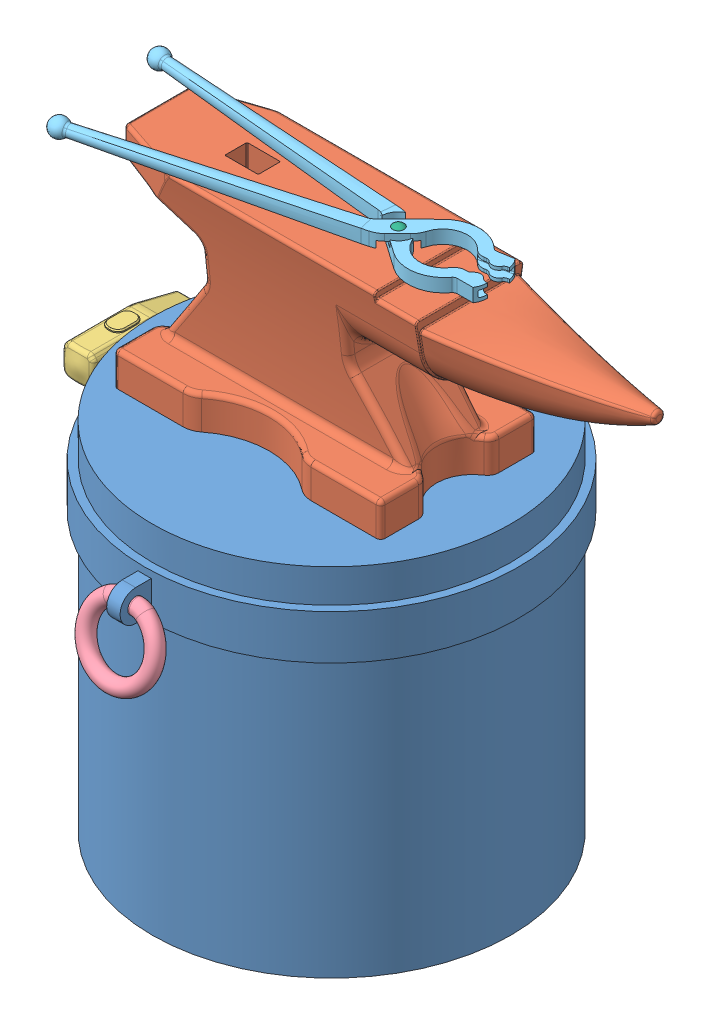
SolidWorks assembly Сборка1, configuration По умолчанию. Lengths in mm.
Overall size (2519.05 2545.47 1870.89).
7 component instances, 6 part files, 11 mates.
Components (placement in the parent):
- Дет0-1: Дет0 [По умолчанию] at (696.6225 706.2106 707.0995) size (1880 1630.94 1820)
- Дет1-1: Дет1 [По умолчанию] at (675.67 2306.2106 715.6378) size (2250 850 700)
- Дет2-1: Дет2 [По умолчанию] at (-243.3775 2146.2106 707.0995) x (0 1 0) z (-1 0 0) size (900 515.77 140.28)
- Дет3-1: Дет3 [По умолчанию] at (696.6225 2056.2106 1617.0995) x (1 0 0) z (0 0.268213 0.96336) size (370 360 70)
- Дет4-1: Дет4 [По умолчанию] at (1012.0301 3196.2106 722.3721) size (1678.58 80 330.31)
- Дет5-1: Дет5 [По умолчанию] at (1012.0301 3196.2106 722.3721) size (50 80 50)
- Дет4-2: Дет4 [По умолчанию] at (1012.0301 3196.2106 722.3721) x (0.98633 0 -0.16478) z (-0.16478 0 -0.98633) size (1678.58 80 330.31)
Mates (geometry in assembly coordinates):
- Совпадение2: coincident anti-aligned: plane of Дет0-1 through (-238.3775 2076.2106 772.0995) normal (0 0 -1); plane of Дет2-1 through (-288.3775 2090.3527 772.0995) normal (0 0 1)
- Совпадение3: coincident anti-aligned: plane of Дет0-1 through (-198.3775 2076.2106 732.0995) normal (-1 0 0); plane of Дет2-1 through (-198.3775 2146.2106 707.0995) normal (1 0 0)
- Совпадение4: coincident anti-aligned: plane of Дет0-1 through (696.6225 2076.2106 707.0995) normal (0 1 0); plane of Дет2-1 through (-313.3775 2076.2106 625.5653) normal (0 -1 0)
- Совпадение5: coincident anti-aligned: plane of Дет0-1 through (666.6225 2056.2106 1617.0995) normal (-1 0 0); plane of Дет3-1 through (666.6225 2056.2106 1617.0995) normal (1 0 0)
- Концентричный1: concentric aligned: cylinder of Дет0-1 through (726.6225 2056.2106 1617.0995) axis (-1 0 0) radius 30; cylinder of Дет3-1 through (646.366 2056.2106 1617.0995) axis (-1 0 0) radius 30
- Совпадение6: coincident anti-aligned: plane of Дет0-1 through (696.6225 2306.2106 707.0995) normal (0 1 0); plane of Дет1-1 through (95.67 2306.2106 385.6378) normal (0 -1 0)
- Совпадение7: coincident anti-aligned: plane of Дет4-1 through (1199.1316 3166.2106 703.4891) normal (0 -1 0); plane of Дет5-1 through (1027.0301 3166.2106 722.3721) normal (0 1 0)
- Концентричный2: concentric anti-aligned: cylinder of Дет4-1 through (1012.0301 3226.2106 722.3721) axis (0 -1 0) radius 15; cylinder of Дет5-1 through (1012.0301 3275.8827 722.3721) axis (0 1 0) radius 15
- Совпадение8: coincident anti-aligned: plane of Дет4-1 through (1012.0301 3196.2106 722.3721) normal (0 1 0); plane of Дет4-2 through (1012.0301 3196.2106 722.3721) normal (0 -1 0)
- Концентричный3: concentric aligned: cylinder of Дет5-1 through (1012.0301 3275.8827 722.3721) axis (0 1 0) radius 15; cylinder of Дет4-2 through (1012.0301 3166.2106 722.3721) axis (0 1 0) radius 15
- Касательность1: tangent anti-aligned: plane of Дет1-1 through (-74.33 3156.2106 965.6378) normal (0 1 0); sphere of Дет5-1
